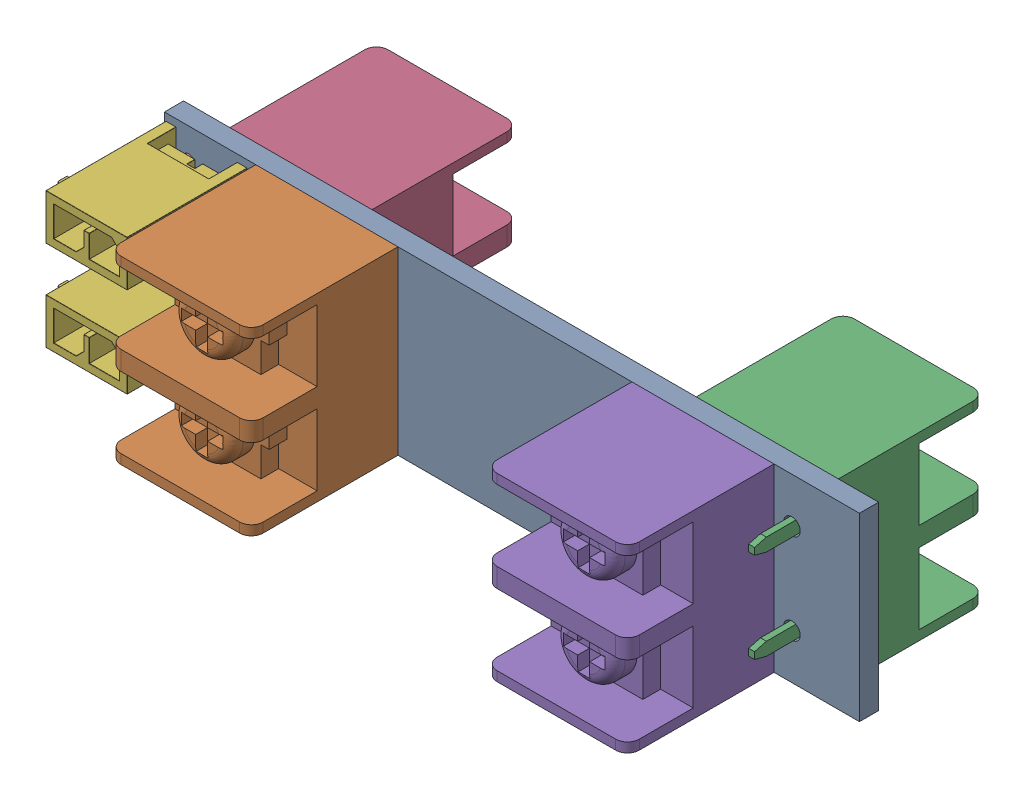
SolidWorks assembly Bulkhead_Through, configuration Default. Lengths in mm.
Overall size (59.97 15.24 26.37).
7 component instances, 3 part files, 0 mates.
Components (placement in the parent):
- Bulkhead_Through_BOARD-1: Bulkhead_Through_BOARD [Default] at origin size (58.67 15.24 1.62)
- KF7.62-2P-Footprint-1_CMP-00780-1-1: KF7.62-2P-Footprint-1_CMP-00780-1 [Default] at (48.26 38.1 1.594) x (0 1 0) z (0 0 1) size (15.24 12 17.4)
- KF7.62-2P-Footprint-1_CMP-00780-1-2: KF7.62-2P-Footprint-1_CMP-00780-1 [Default] at (83.82 38.1 0.0254) x (0 -1 0) z (0 0 -1) size (15.24 12 17.4)
- KF7.62-2P-Footprint-1_CMP-00780-1-3: KF7.62-2P-Footprint-1_CMP-00780-1 [Default] at (44.45 38.1 0.0254) x (0 1 0) z (0 0 -1) size (15.24 12 17.4)
- KF7.62-2P-Footprint-1_CMP-00780-1-4: KF7.62-2P-Footprint-1_CMP-00780-1 [Default] at (80.01 38.1 1.594) x (0 -1 0) z (0 0 1) size (15.24 12 17.4)
- FP-206832-0201-EDIT_CMP-048-000004-3-1: FP-206832-0201-EDIT_CMP-048-000004-3 [Default] at (38.1 43.18 1.594) x (0 -1 0) z (0 0 1) size (3.89 8.3 13.36)
- FP-206832-0201-EDIT_CMP-048-000004-3-2: FP-206832-0201-EDIT_CMP-048-000004-3 [Default] at (38.1 35.56 1.594) x (0 -1 0) z (0 0 1) size (3.89 8.3 13.36)
